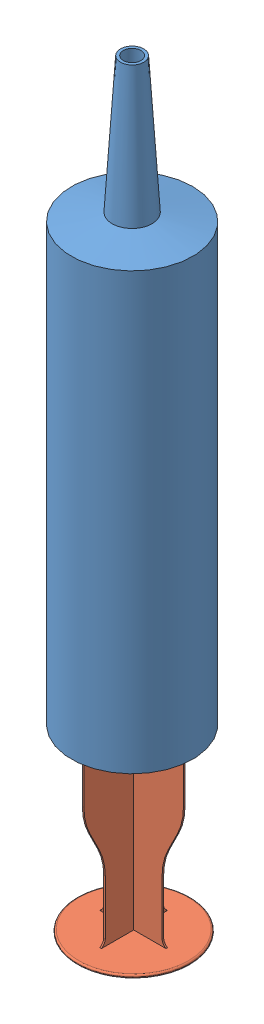
SolidWorks assembly Syringe, configuration Default. Lengths in mm.
Overall size (31.2 195.46 31.2).
3 component instances, 3 part files, 3 mates.
Components (placement in the parent):
- Syringe_barrel-1: Syringe_barrel [默认] at (31.2902 17.5526 117.4949) size (31.2 149 31.2)
- Syringe_plunger-1: Syringe_plunger [默认] at (31.4902 -28.908 117.2949) x (0 0 -1) z (1 0 0) size (29 126.4 29)
- Syringe_plunger_rubber-1: Syringe_plunger_rubber [默认] at (31.1642 88.772 117.9123) x (1 0 0) z (0 -1 0) size (29.91 29.91 12.8)
Mates (geometry in assembly coordinates):
- 重合1: coincident: point of Syringe_plunger-1; circle of Syringe_plunger_rubber-1
- 平行1: parallel anti-aligned: plane of Syringe_plunger-1 through (31.4902 91.292 117.2949) normal (0 1 0); plane of Syringe_plunger_rubber-1 through (40.8642 88.772 117.9123) normal (0 -1 0)
- 同心1: concentric aligned: cylinder of Syringe_barrel-1 through (31.2902 166.5526 117.4949) axis (0 -1 0) radius 15.6; line of Syringe_plunger-1 through (31.2902 90.092 117.4949) axis (0 -1 0)
